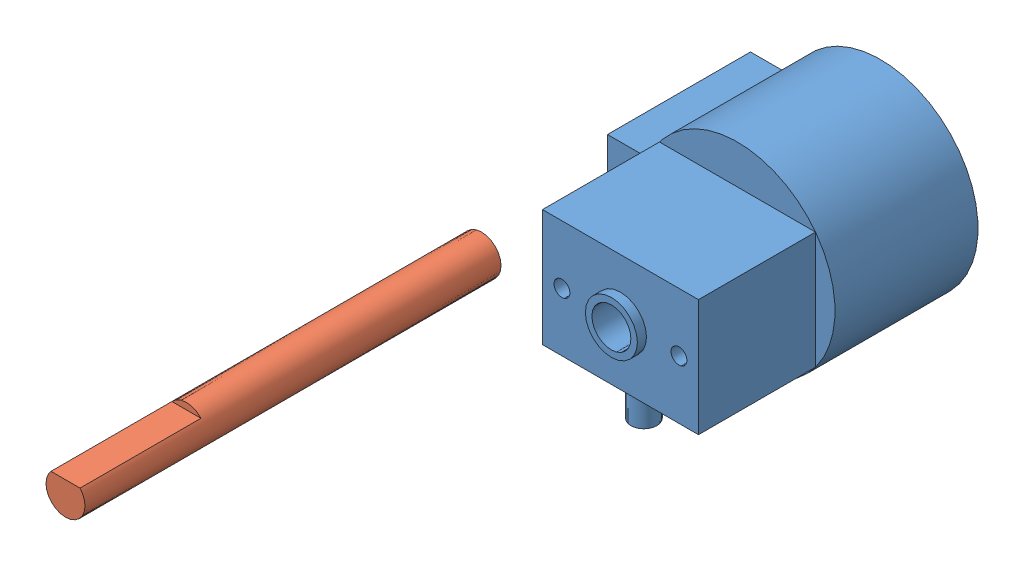
SolidWorks assembly motor-gm15by, configuration Default. Lengths in mm.
Overall size (21 23.5 51.69).
2 component instances, 2 part files, 0 mates.
Components (placement in the parent):
- Motor-Body_1-1: Motor-Body_1 [Default] x (0 1 0) z (1 0 0) size (23.5 21.7 17.5)
- Motor-Shaft_1-1: Motor-Shaft_1 [Default] at (-11.9994 -2.1508 18.6884) x (0 -1 0) z (1 0 0) size (3 32 3)
